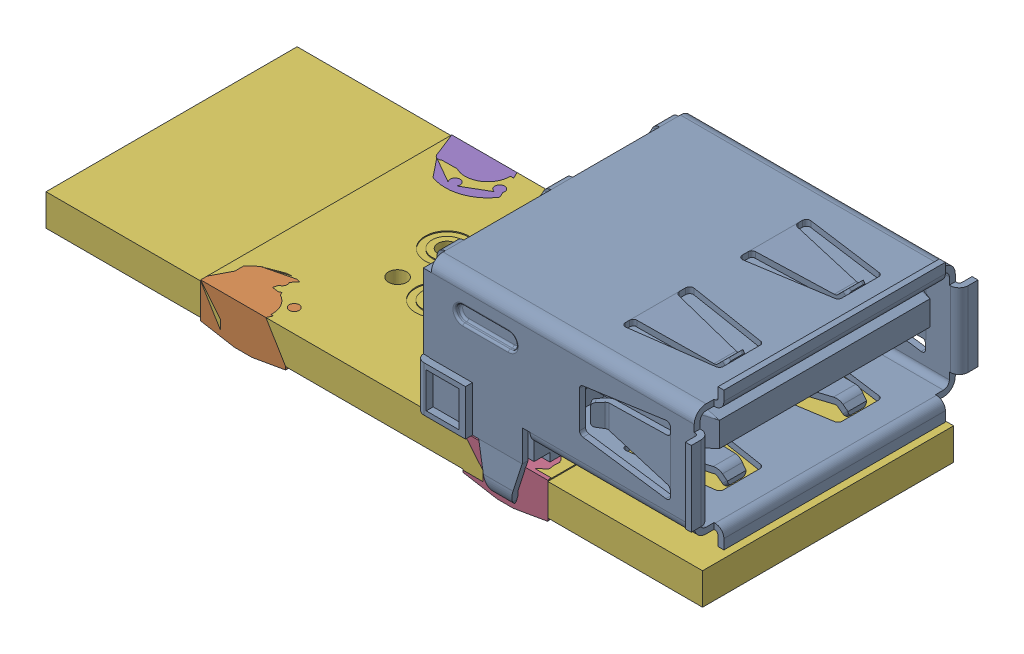
SolidWorks assembly 3AC11-010___, configuration Default. Lengths in mm.
Overall size (33.53 9.83 14.5).
2 component instances, 2 part files, 0 mates.
Components (placement in the parent):
- 1AA05-019-SUZHOU___-1: 1AA05-019-SUZHOU___ [Default] at (3.13 5.8 0) x (0 0 -1) z (1 0 0) size (14.5 9.83 14.2)
- 1BC01-017+COMPONENT_Rev.-1: 1BC01-017+COMPONENT_Rev. [Default] at origin size (33.2 2.1 12.7)
